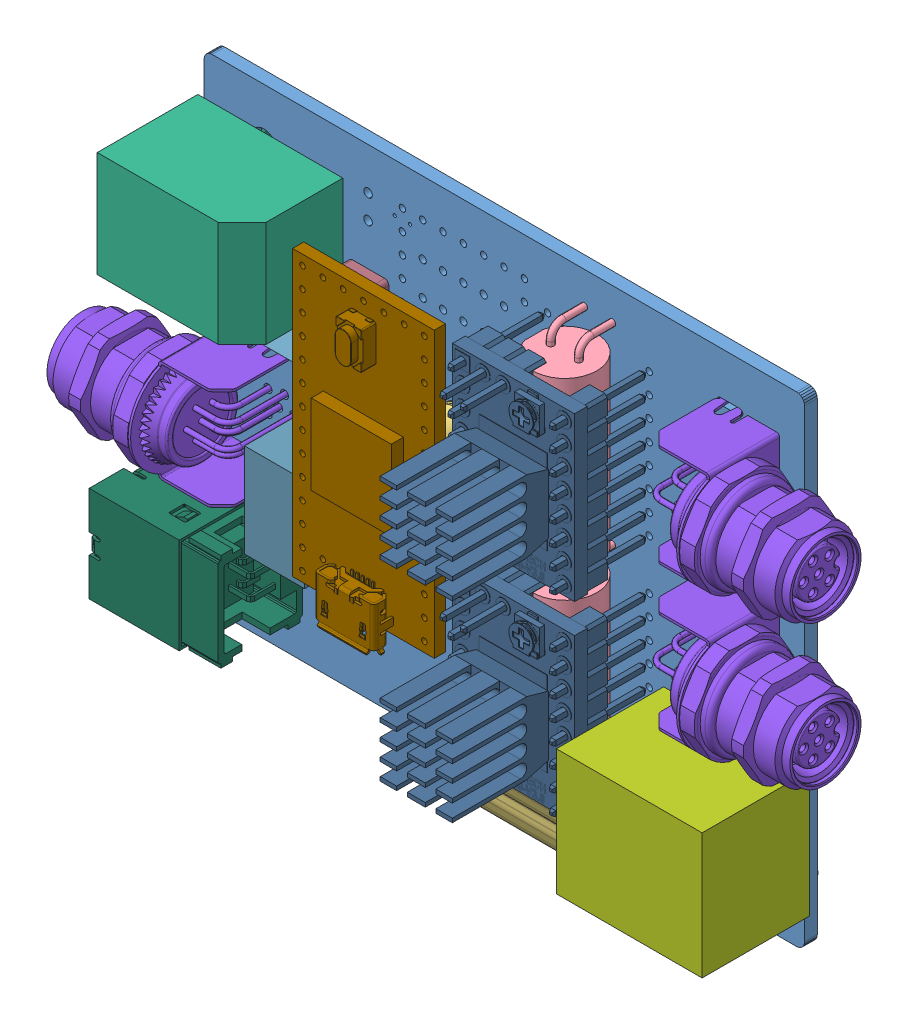
SolidWorks assembly tiny, configuration Default. Lengths in mm.
Overall size (92.8 60 28.45).
20 component instances, 15 part files, 0 mates.
Components (placement in the parent):
- Board_tiny-1: Board_tiny [Default] at origin size (75 60 1.59)
- clip_CR1620-1: clip_CR1620 [Default] at (24.987 11.8475 -1.5896) x (1 0 0) z (0 1 0) size (17.19 6.9 15.1)
- cappr-2.54_5.08-1: cappr-2.54_5.08 [Default] at (32.7063 35.8775 -2.286) size (5.3 5.59 9.46)
- D8x20coude-1: D8x20coude [Default] at (49.25 54 4.2) x (1 0 0) z (0 -1 0) size (7.87 11 23.4)
- D8x20coude-2: D8x20coude [Default] at (49.25 30 4.2) x (1 0 0) z (0 -1 0) size (7.87 11 23.4)
- diode_SMD_DO214_S5DC-13-F-1: diode_SMD_DO214_S5DC-13-F [Default] at (11.8988 37.1587 0) x (-1 0 0) z (0 0 1) size (7.94 5.9 2.5)
- SS-90000-003-1: SS-90000-003 [Default] at (17.64 48.5 6.604) x (0 -1 0) z (-1 0 0) size (13.21 15.57 18.1)
- RJE091884111A-1: RJE091884111A [Default] at (61.595 7.6 0) x (0 1 0) z (0 0 1) size (16.9 18.2 18.5)
- M8_6pin_elbow_PCB-1: M8_6pin_elbow_PCB [Default] at (65.7 48 -2.413) x (0 1 0) z (0 0 1) size (12.8 20.4 15.35)
- M8_6pin_elbow_PCB-2: M8_6pin_elbow_PCB [Default] at (65.7 30 -2.413) x (0 1 0) z (0 0 1) size (12.8 20.4 15.35)
- M8_6pin_elbow_PCB-3: M8_6pin_elbow_PCB [Default] at (9.3 26 -2.413) x (0 -1 0) z (0 0 1) size (12.8 20.4 15.35)
- Teensy_4.0_Assembly-1: Teensy_4.0_Assembly [Default] at (22.985 71.735 0) x (0 1 0) z (1 0 0) size (36.75 4.12 17.7)
- TMC2130-V3.0-1: TMC2130-V3.0 [Default] at (49.25 44.2 9) x (1 0 0) z (0 -1 0) size (15.24 22.13 20.32)
- TMC2130-V3.0-2: TMC2130-V3.0 [Default] at (49.25 20.2 9) x (1 0 0) z (0 -1 0) size (15.24 22.13 20.32)
- sip-6_14.7x2x2.54-1: sip-6_14.7x2x2.54 [Default] at (27.305 37.8825 -2) x (0 1 0) z (0 0 1) size (14.8 2.16 7.95)
- sip-8_21.6x2.4x2.54-1: sip-8_21.6x2.4x2.54 [Default] at (44.7675 7.4025 -2) x (-1 0 0) z (0 0 1) size (22.07 2.4 10.48)
- sip-8_21.6x2.4x2.54-2: sip-8_21.6x2.4x2.54 [Default] at (44.7675 4.545 -2) x (-1 0 0) z (0 0 1) size (22.07 2.4 10.48)
- suport_fusible_SMD-1: suport_fusible_SMD [Default] at (20.55 41.6825 0) x (1 0 0) z (0 -1 0) size (5.03 3.81 9.73)
- TSR_1-2450-1: TSR_1-2450 [Default] at (19.1038 24.13 5.5) x (0 -1 0) z (-1 0 0) size (11.7 14.2 7.55)
- 924-1: 924 [Default] at (8.8 11 0.2) x (0 -1 0) z (0 0 1) size (14.31 15.66 15.33)
